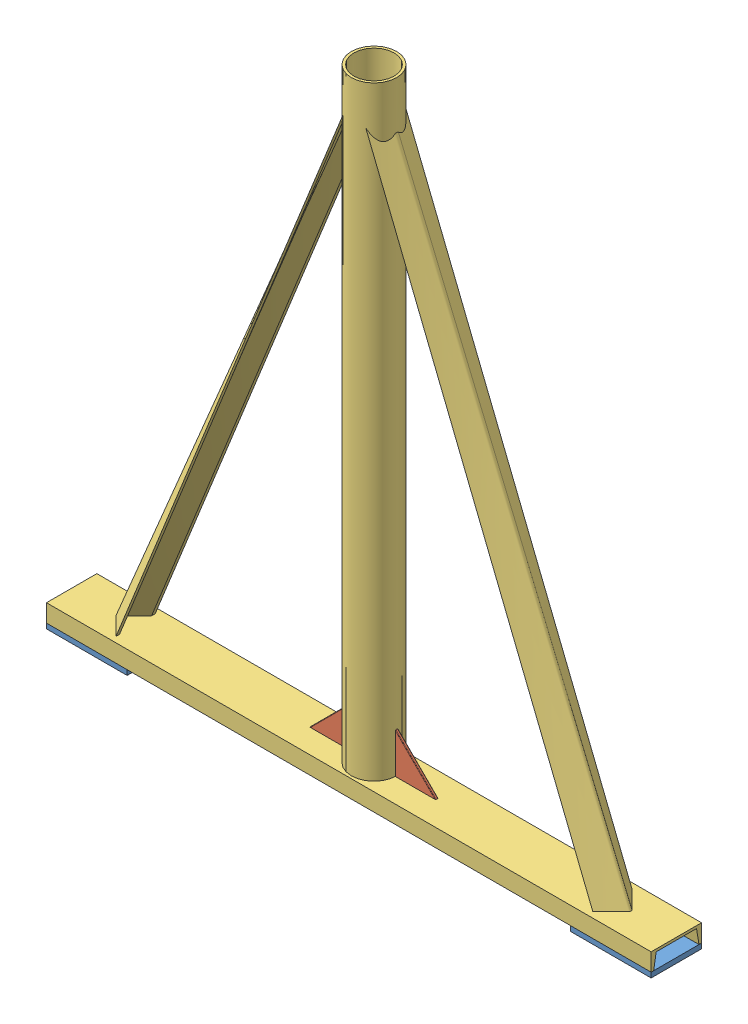
SolidWorks assembly SubAssembly 1, configuration Default. Lengths in mm.
Overall size (1524 1581.15 127).
5 component instances, 3 part files, 16 mates.
Components (placement in the parent):
- Part 2-1: Part 2 [Default] at (-30.7446 140.2661 83.6839) size (203.2 12.7 127)
- Part 6-1: Part 6 [Default] at (674.1054 184.7161 144.0089) size (101.6 101.6 6.35)
- SA 1 Part-1: SA 1 Part [Default] at (-30.7446 184.7161 147.1839) x (0 0 -1) z (1 0 0) size (127 1568.45 1524)
- Part 2-2: Part 2 [Default] at (1493.2554 140.2661 210.6839) x (-1 0 0) z (0 0 -1) size (203.2 12.7 127)
- Part 6-2: Part 6 [Default] at (788.4054 184.7161 150.3589) x (-1 0 0) z (0 0 -1) size (101.6 101.6 6.35)
Mates (geometry in assembly coordinates):
- Coincident1: coincident anti-aligned: plane of SA 1 Part-1 through (1493.2554 140.2661 90.0339) normal (0 -1 0); plane of Part 2-2 through (1493.2554 140.2661 83.6839) normal (0 1 0)
- Parallel1: parallel aligned: plane of SA 1 Part-1 through (1493.2554 140.2661 83.6839) normal (0 0 -1); plane of Part 2-2 through (1493.2554 140.2661 83.6839) normal (0 0 -1)
- Coincident3: coincident aligned: plane of SA 1 Part-1 through (1493.2554 184.7161 210.6839) normal (0 0 1); plane of Part 2-2 through (1493.2554 140.2661 210.6839) normal (0 0 1)
- Coincident4: coincident aligned: plane of SA 1 Part-1 through (1493.2554 184.7161 147.1839) normal (1 0 0); plane of Part 2-2 through (1493.2554 127.5661 83.6839) normal (1 0 0)
- Coincident5: coincident anti-aligned: plane of Part 2-1 through (-30.7446 140.2661 210.6839) normal (0 1 0); plane of SA 1 Part-1 through (1493.2554 140.2661 90.0339) normal (0 -1 0)
- Coincident6: coincident aligned: plane of Part 2-1 through (-30.7446 140.2661 83.6839) normal (0 0 -1); plane of SA 1 Part-1 through (1493.2554 140.2661 83.6839) normal (0 0 -1)
- Coincident7: coincident aligned: plane of Part 2-1 through (-30.7446 140.2661 83.6839) normal (0 0 -1); plane of SA 1 Part-1 through (1493.2554 140.2661 83.6839) normal (0 0 -1)
- Coincident8: coincident aligned: plane of Part 2-1 through (-30.7446 127.5661 210.6839) normal (-1 0 0); plane of SA 1 Part-1 through (-30.7446 184.7161 147.1839) normal (-1 0 0)
- Coincident10: coincident anti-aligned: plane of Part 6-1 through (674.1054 184.7161 150.3589) normal (0 -1 0); plane of SA 1 Part-1 through (1493.2554 184.7161 83.6839) normal (0 1 0)
- Parallel2: parallel aligned: plane of Part 6-1 through (674.1054 184.7161 144.0089) normal (0 0 -1); plane of SA 1 Part-1 through (1493.2554 140.2661 83.6839) normal (0 0 -1)
- Width1: width anti-aligned: plane of Part 6-1 through (674.1054 184.7161 150.3589) normal (0 0 1); plane of SA 1 Part-1 through (674.1054 184.7161 144.0089) normal (0 0 -1); plane of Part 6-1 through (1493.2554 140.2661 83.6839) normal (0 0 -1); plane of SA 1 Part-1 through (1493.2554 184.7161 210.6839) normal (0 0 1)
- Distance1: distance = 704.85 mm anti-aligned: plane of Part 6-1 through (674.1054 286.3161 150.3589) normal (1 0 0); plane of SA 1 Part-1 through (-30.7446 184.7161 147.1839) normal (-1 0 0)
- Coincident13: coincident anti-aligned: plane of SA 1 Part-1 through (1493.2554 184.7161 83.6839) normal (0 1 0); plane of Part 6-2 through (788.4054 184.7161 144.0089) normal (0 -1 0)
- Parallel3: parallel anti-aligned: plane of SA 1 Part-1 through (1493.2554 184.7161 210.6839) normal (0 0 1); plane of Part 6-2 through (788.4054 184.7161 144.0089) normal (0 0 -1)
- Width2: width anti-aligned: plane of Part 6-2 through (788.4054 184.7161 150.3589) normal (0 0 1); plane of SA 1 Part-1 through (788.4054 184.7161 144.0089) normal (0 0 -1); plane of Part 6-2 through (1493.2554 140.2661 83.6839) normal (0 0 -1); plane of SA 1 Part-1 through (1493.2554 184.7161 210.6839) normal (0 0 1)
- Distance3: distance = 704.85 mm anti-aligned: plane of Part 6-2 through (788.4054 286.3161 144.0089) normal (-1 0 0); plane of SA 1 Part-1 through (1493.2554 184.7161 147.1839) normal (1 0 0)
